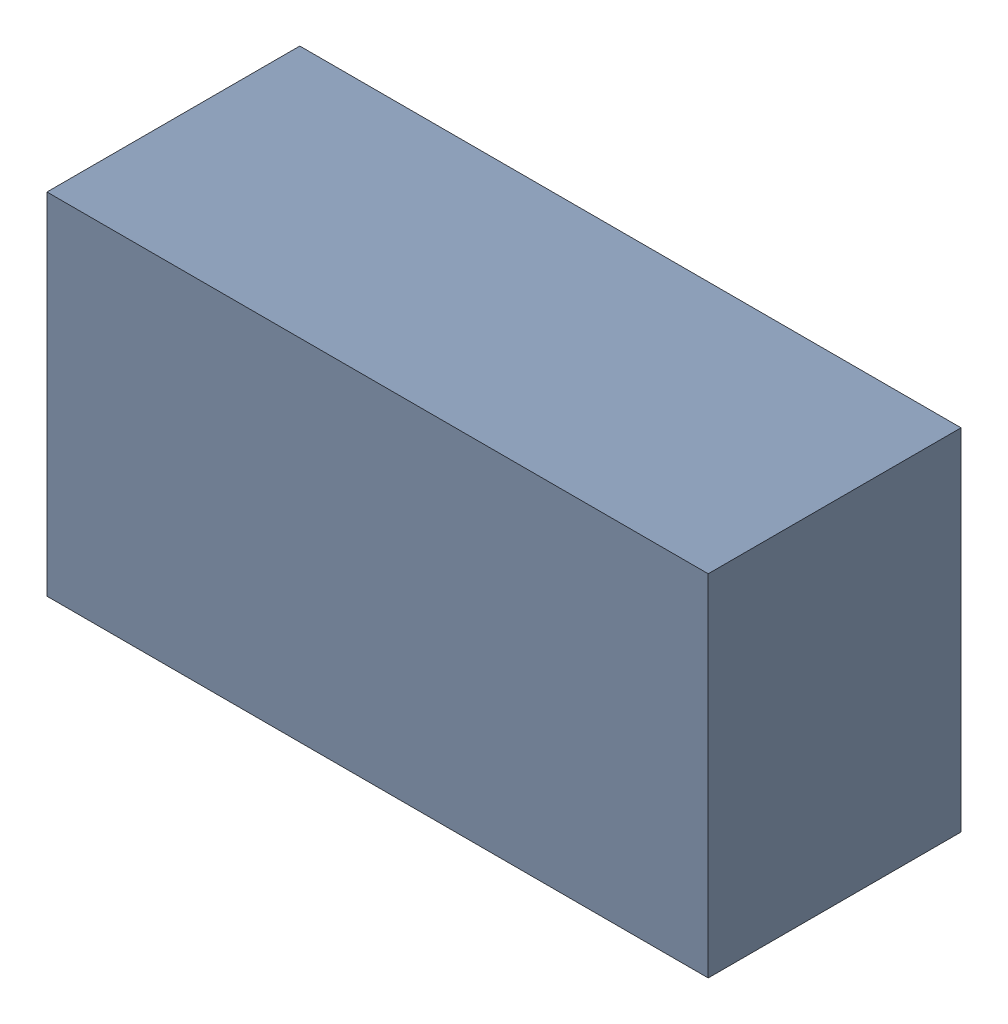
SolidWorks assembly C101, configuration Standard. Lengths in mm.
Overall size (3.4 1.8 1.3).
2 component instances, 1 part files, 0 mates.
Components (placement in the parent):
- 885542104-1: 885542104 [Standard] at (-11.645 14.5 0) size (3.4 1.8 1.3)
  - Extruded_29-1: Extruded_29 [Standard] at origin size (3.4 1.8 1.3)
